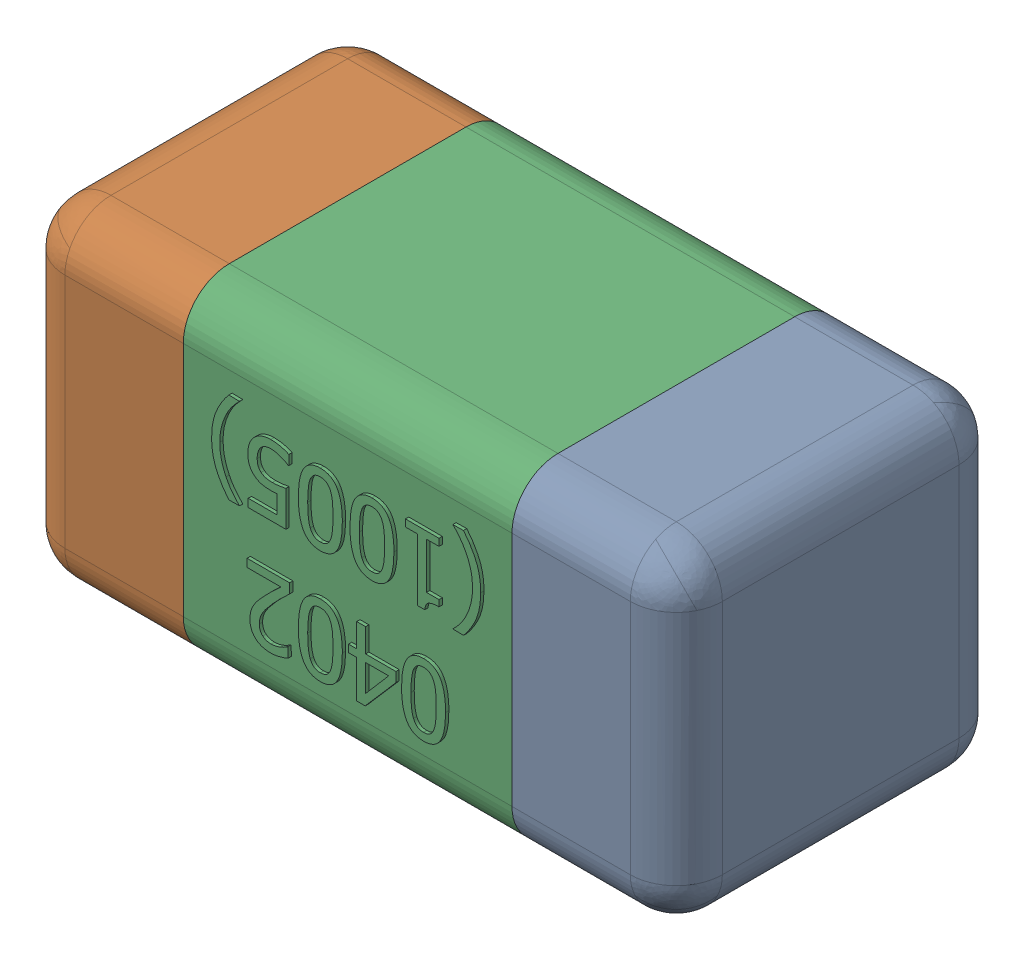
SolidWorks assembly C5, configuration Standard. Lengths in mm.
Overall size (1.01 0.51 0.51).
4 component instances, 3 part files, 0 mates.
Components (placement in the parent):
- C5-subassembly-1-1: C5-subassembly-1 [Standard] at (5.8999 -2 0) x (-1 0 0) z (0 0 1) size (1.01 0.51 0.51)
  - User Library-0402_Cap-1: User Library-0402_Cap [Standard] at origin size (0.26 0.51 0.51)
  - User Library-0402_Cap-1-1: User Library-0402_Cap-1 [Standard] at origin size (0.26 0.5 0.51)
  - User Library-0402_Cap-2-1: User Library-0402_Cap-2 [Standard] at origin size (0.5 0.5 0.51)
